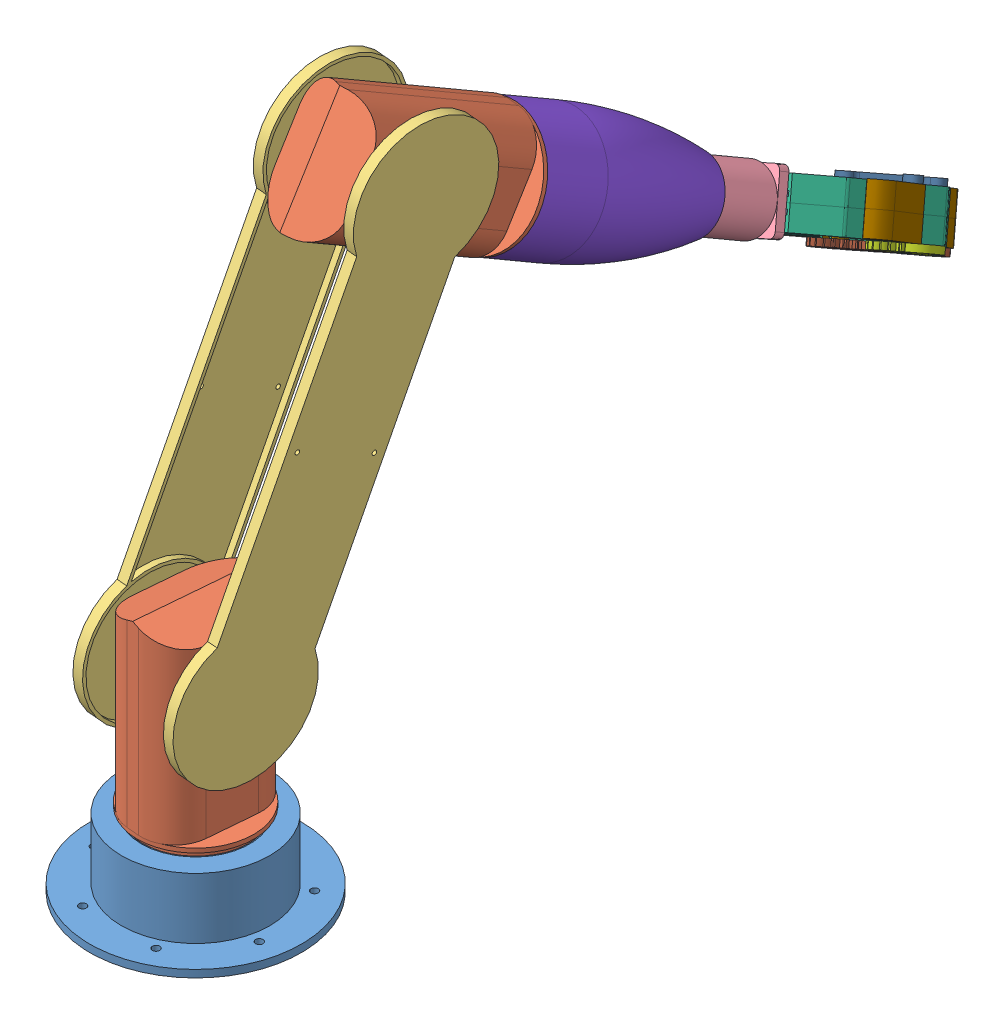
SolidWorks assembly robotic arm, configuration Default. Lengths in mm.
Overall size (112.51 303.58 382.68).
22 component instances, 12 part files, 42 mates.
Components (placement in the parent):
- base robot-1: base robot [Default] at (1.4403 12.4441 72.5801) size (100 32.2 100)
- hombrom robot-1: hombrom robot [Default] at (1.4403 49.6441 72.5801) x (-0.996236 0 -0.08668) z (-0.08668 0 0.996236) size (55 90.92 55)
- robot lateral-1: robot lateral [Default] at (-21.0498 188.2804 31.1109) x (0.036202 0.908608 -0.416079) z (0.996236 0 0.08668) size (252 63.5 8)
- robotarm1-1: robotarm1 [Default] at (22.4785 185.0491 -169.2166) x (0.927783 0.355674 -0.112755) z (0.076209 -0.476463 -0.875885) size (27.94 27.75 32.75)
- robotarm2-1: robotarm2 [Default] at (24.1156 180.8277 -169.0612) x (-0.076209 0.476463 0.875885) z (0.927783 0.355674 -0.112755) size (14 10 20)
- robotarm3-1: robotarm3 [Default] at (25.5753 158.2899 -228.1443) x (-0.927783 -0.355674 0.112755) z (-0.076209 0.476463 0.875885) size (41 10 82)
- robotarm5-1: robotarm5 [Default] at (44.119 149.8671 -221.8466) x (0.700809 0.569229 0.429937) z (0.612746 -0.171756 -0.77139) size (46.27 3 30.4)
- rotor robot-1: rotor robot [Default] at (15.4052 229.2716 -87.9219) x (0.955999 0.284504 -0.071585) z (-0.2833 0.83189 -0.47718) size (55 100.8 55)
- robot lateral-2: robot lateral [Default] at (30.7545 188.2804 35.6183) x (0.036202 0.908608 -0.416079) z (-0.996236 0 -0.08668) size (252 63.5 8)
- hombrom robot-2: hombrom robot [Default] at (12.3035 248.6641 -52.2727) x (-0.996236 0 -0.08668) z (-0.0413 -0.879194 0.47467) size (55 90.92 55)
- robotarm2-2: robotarm2 [Default] at (21.1461 187.3645 -172.8755) x (-0.076209 0.476463 0.875885) z (-0.927783 -0.355674 0.112755) size (14 10 20)
- robotarm3-2: robotarm3 [Default] at (29.2278 150.2495 -223.4527) x (-0.927783 -0.355674 0.112755) z (-0.076209 0.476463 0.875885) size (41 10 82)
- robotarm7-3: robotarm7 [Default] at (38.4459 147.7495 -234.9136) x (-0.365254 0.804039 -0.46916) z (-0.305764 -0.57964 -0.755332) size (10 10.69 76.99)
- robotarm7-4: robotarm7 [Default] at (34.7934 155.7899 -239.6053) x (-0.365254 0.804039 -0.46916) z (-0.305764 -0.57964 -0.755332) size (10 10.69 76.99)
- robotarm6-3: robotarm6 [Default] at (37.5467 141.412 -228.0229) x (-0.56216 -0.59222 -0.577279) z (-0.365254 0.804039 -0.46916) size (38 7 3)
- robotarm6-4: robotarm6 [Default] at (29.1459 159.9049 -238.8136) x (-0.56216 -0.59222 -0.577279) z (-0.365254 0.804039 -0.46916) size (38 7 3)
- Part11^robotic arm-1: Part11^robotic arm [Default] at origin (virtual)
- robotarm4-2: robotarm4 [Default] at (19.5122 139.8433 -219.8682) x (0.54358 -0.224923 -0.80866) z (-0.755719 -0.550392 -0.354905) size (49.54 3 29.07)
- robotarm7-7: robotarm7 [Default] at (18.1758 149.4194 -237.5857) x (0.365254 -0.804039 0.46916) z (0.445144 -0.291772 -0.846591) size (10 10.69 76.99)
- robotarm7-8: robotarm7 [Default] at (21.8283 141.379 -232.8941) x (0.365254 -0.804039 0.46916) z (0.445144 -0.291772 -0.846591) size (10 10.69 76.99)
- robotarm6-5: robotarm6 [Default] at (18.6049 158.6961 -239.0732) x (0.675705 -0.117673 -0.727719) z (0.365254 -0.804039 0.46916) size (38 7 3)
- robotarm6-6: robotarm6 [Default] at (27.0057 140.2032 -228.2825) x (0.675705 -0.117673 -0.727719) z (0.365254 -0.804039 0.46916) size (38 7 3)
Mates (geometry in assembly coordinates):
- Concentric1: concentric anti-aligned: cylinder of base robot-1 through (1.4403 44.6441 72.5801) axis (0 -1 0) radius 25.5; cylinder of hombrom robot-1 through (1.4403 44.6441 72.5801) axis (0 1 0) radius 25
- Coincident1: coincident anti-aligned: plane of base robot-1 through (1.4403 44.6441 72.5801) normal (0 1 0); plane of hombrom robot-1 through (1.4403 44.6441 72.5801) normal (0 -1 0)
- Concentric2: concentric anti-aligned: cylinder of hombrom robot-1 through (-22.4694 102.6441 70.4997) axis (0.996236 0 0.08668) radius 2.5; cylinder of robot lateral-1 through (-16.4919 102.6441 71.0198) axis (-0.996236 0 -0.08668) radius 5.75
- Coincident2: coincident aligned: circle of hombrom robot-1; plane of robot lateral-1 through (-22.4694 102.6441 70.4997) normal (0.996236 0 0.08668)
- Concentric3: concentric anti-aligned: cylinder of hombrom robot-1 through (25.35 102.6441 74.6604) axis (-0.996236 0 -0.08668) radius 2.5; cylinder of robot lateral-2 through (19.3726 102.6441 74.1403) axis (0.996236 0 0.08668) radius 5.75
- Coincident3: coincident anti-aligned: plane of hombrom robot-1 through (25.35 102.6441 74.6604) normal (0.996236 0 0.08668); plane of robot lateral-2 through (25.35 102.6441 74.6604) normal (-0.996236 0 -0.08668)
- Concentric4: concentric anti-aligned: cylinder of robot lateral-1 through (-9.6679 273.9166 -7.4111) axis (-0.996236 0 -0.08668) radius 5.75; cylinder of hombrom robot-2 through (-15.6453 273.9166 -7.9311) axis (0.996236 0 0.08668) radius 2.5
- Coincident4: coincident anti-aligned: plane of robot lateral-1 through (-22.4694 102.6441 70.4997) normal (0.996236 0 0.08668); plane of hombrom robot-2 through (-15.6453 273.9166 -7.9311) normal (-0.996236 0 -0.08668)
- Concentric5: concentric anti-aligned: cylinder of robot lateral-2 through (26.1966 273.9166 -4.2906) axis (0.996236 0 0.08668) radius 5.75; cylinder of hombrom robot-2 through (32.1741 273.9166 -3.7705) axis (-0.996236 0 -0.08668) radius 2.5
- Concentric6: concentric anti-aligned: cylinder of rotor robot-1 through (20.1377 199.6836 -142.3137) axis (0.076209 -0.476463 -0.875885) radius 27.5; cylinder of hombrom robot-2 through (12.6845 246.2817 -56.6522) axis (-0.076209 0.476463 0.875885) radius 25
- Coincident5: coincident anti-aligned: plane of rotor robot-1 through (38.7458 255.535 -55.9931) normal (-0.076209 0.476463 0.875885); plane of hombrom robot-2 through (12.4559 247.7111 -54.0245) normal (0.076209 -0.476463 -0.875885)
- Coincident6: coincident anti-aligned: plane of robotarm1-1 through (20.1377 199.6836 -142.3137) normal (-0.076209 0.476463 0.875885); plane of rotor robot-1 through (33.3001 203.6007 -143.2993) normal (0.076209 -0.476463 -0.875885)
- Concentric7: concentric anti-aligned: circle of robotarm1-1; circle of rotor robot-1
- Coincident7: coincident anti-aligned: plane of robotarm1-1 through (22.4785 185.0491 -169.2166) normal (0.076209 -0.476463 -0.875885); plane of robotarm2-2 through (8.7938 191.193 -173.7494) normal (-0.076209 0.476463 0.875885)
- Coincident8: coincident anti-aligned: plane of robotarm1-1 through (30.245 198.389 -178.1174) normal (0.365254 -0.804039 0.46916); plane of robotarm2-2 through (8.9463 190.2401 -175.5012) normal (-0.365254 0.804039 -0.46916)
- Width1: width aligned: plane of robotarm2-2 through (30.2111 191.1626 -174.9938) normal (0.927783 0.355674 -0.112755); plane of robotarm1-1 through (12.6549 181.8488 -171.4548) normal (-0.927783 -0.355674 0.112755); plane of robotarm2-2 through (6.208 189.1742 -175.1961) normal (0.927783 0.355674 -0.112755); plane of robotarm1-1 through (30.245 198.389 -178.1174) normal (-0.927783 -0.355674 0.112755)
- Coincident9: coincident anti-aligned: plane of robotarm2-1 through (36.1631 178.9051 -164.6837) normal (-0.076209 0.476463 0.875885); plane of robotarm1-1 through (22.4785 185.0491 -169.2166) normal (0.076209 -0.476463 -0.875885)
- Coincident11: coincident anti-aligned: plane of robotarm1-1 through (39.0586 178.9876 -166.7966) normal (-0.365254 0.804039 -0.46916); plane of robotarm2-1 through (36.3155 177.9521 -166.4355) normal (0.365254 -0.804039 0.46916)
- Width2: width anti-aligned: plane of robotarm2-1 through (32.7191 185.6416 -171.7722) normal (0.927783 0.355674 -0.112755); plane of robotarm1-1 through (15.163 176.3278 -168.2332) normal (-0.927783 -0.355674 0.112755); plane of robotarm2-1 through (30.245 198.389 -178.1174) normal (-0.927783 -0.355674 0.112755); plane of robotarm1-1 through (6.208 189.1742 -175.1961) normal (0.927783 0.355674 -0.112755)
- Coincident13: coincident aligned: plane of robotarm3-1 through (33.2175 185.6262 -176.5881) normal (-0.076209 0.476463 0.875885); plane of robotarm3-2 through (36.8701 177.5858 -171.8965) normal (-0.076209 0.476463 0.875885)
- Coincident14: coincident aligned: plane of robotarm3-1 through (47.1832 156.7963 -236.8688) normal (0.927783 0.355674 -0.112755); plane of robotarm3-2 through (50.8357 148.756 -232.1772) normal (0.927783 0.355674 -0.112755)
- Coincident15: coincident aligned: plane of robotarm3-1 through (33.2175 185.6262 -176.5881) normal (-0.076209 0.476463 0.875885); plane of robotarm3-2 through (36.8701 177.5858 -171.8965) normal (-0.076209 0.476463 0.875885)
- Coincident16: coincident anti-aligned: plane of robotarm3-1 through (27.4015 154.2697 -225.7985) normal (0.365254 -0.804039 0.46916); plane of robotarm3-2 through (27.4015 154.2697 -225.7985) normal (-0.365254 0.804039 -0.46916)
- Width3: width anti-aligned: plane of robotarm3-1 through (23.749 162.31 -230.4901) normal (-0.365254 0.804039 -0.46916); plane of robotarm2-2 through (31.0541 146.2293 -221.1069) normal (0.365254 -0.804039 0.46916); plane of robotarm3-2 through (12.5988 182.1997 -170.8096) normal (0.365254 -0.804039 0.46916); plane of robotarm2-1 through (32.663 185.9925 -171.1271) normal (-0.365254 0.804039 -0.46916)
- Concentric10: concentric aligned: cylinder of robotarm3-1 through (28.8835 181.942 -179.5278) axis (-0.365254 0.804039 -0.46916) radius 1.5; cylinder of robotarm2-2 through (28.1292 183.6023 -180.4966) axis (-0.365254 0.804039 -0.46916) radius 1.5
- Concentric11: concentric aligned: cylinder of robotarm3-1 through (17.7501 177.6739 -178.1748) axis (-0.365254 0.804039 -0.46916) radius 1.5; cylinder of robotarm2-2 through (16.9958 179.3343 -179.1436) axis (-0.365254 0.804039 -0.46916) radius 1.5
- Concentric13: concentric aligned: cylinder of robotarm5-1 through (44.6749 148.6188 -221.2216) axis (-0.365254 0.804039 -0.46916) radius 1.5; cylinder of robotarm3-2 through (43.5791 151.0309 -222.6291) axis (-0.365254 0.804039 -0.46916) radius 1.5
- Coincident21: coincident anti-aligned: plane of robotarm5-1 through (43.5791 151.0309 -222.6291) normal (-0.365254 0.804039 -0.46916); plane of robotarm3-2 through (31.0541 146.2293 -221.1069) normal (0.365254 -0.804039 0.46916)
- Concentric22: concentric anti-aligned: cylinder of robotarm3-2 through (27.7374 134.6447 -238.3782) axis (-0.365254 0.804039 -0.46916) radius 1.5; cylinder of robotarm6-3 through (27.7374 134.6447 -238.3782) axis (0.365254 -0.804039 0.46916) radius 1.5
- Coincident38: coincident anti-aligned: plane of robotarm3-2 through (31.0541 146.2293 -221.1069) normal (0.365254 -0.804039 0.46916); plane of robotarm6-3 through (36.4509 143.8241 -229.4304) normal (-0.365254 0.804039 -0.46916)
- Coincident40: coincident anti-aligned: plane of robotarm3-1 through (23.749 162.31 -230.4901) normal (-0.365254 0.804039 -0.46916); plane of robotarm6-4 through (29.1459 159.9049 -238.8136) normal (0.365254 -0.804039 0.46916)
- Concentric28: concentric anti-aligned: cylinder of robotarm3-1 through (24.0849 142.6851 -243.0698) axis (-0.365254 0.804039 -0.46916) radius 1.5; cylinder of robotarm6-4 through (19.3366 153.1376 -249.1689) axis (0.365254 -0.804039 0.46916) radius 1.5
- Coincident49: coincident anti-aligned: plane of robotarm3-2 through (31.0541 146.2293 -221.1069) normal (0.365254 -0.804039 0.46916); plane of robotarm4-2 through (17.1158 134.6013 -230.1835) normal (-0.365254 0.804039 -0.46916)
- Concentric32: concentric aligned: cylinder of robotarm3-2 through (18.529 141.4277 -219.5847) axis (-0.365254 0.804039 -0.46916) radius 1.5; cylinder of robotarm4-2 through (19.6247 139.0156 -218.1772) axis (-0.365254 0.804039 -0.46916) radius 1.5
- Coincident57: coincident anti-aligned: plane of robotarm7-3 through (36.6197 151.7697 -237.2595) normal (-0.365254 0.804039 -0.46916); plane of robotarm7-4 through (36.6197 151.7697 -237.2595) normal (0.365254 -0.804039 0.46916)
- Coincident58: coincident aligned: plane of robotarm7-3 through (41.016 152.4319 -239.5473) normal (0.87926 0.132435 -0.457562); plane of robotarm7-4 through (37.3634 160.4723 -244.2389) normal (0.87926 0.132435 -0.457562)
- Concentric38: concentric aligned: cylinder of robotarm7-3 through (31.7274 142.4954 -249.3448) axis (0.365254 -0.804039 0.46916) radius 1.5; cylinder of robotarm7-4 through (28.0749 150.5358 -254.0364) axis (0.365254 -0.804039 0.46916) radius 1.5
- Concentric39: concentric anti-aligned: cylinder of robotarm7-3 through (31.7274 142.4954 -249.3448) axis (0.365254 -0.804039 0.46916) radius 1.5; cylinder of robotarm4-2 through (36.4757 132.0429 -243.2457) axis (-0.365254 0.804039 -0.46916) radius 1.5
- Concentric40: concentric aligned: cylinder of robotarm7-3 through (41.5119 161.0439 -225.1741) axis (0.365254 -0.804039 0.46916) radius 1.5; cylinder of robotarm6-4 through (36.7636 171.4964 -231.2732) axis (0.365254 -0.804039 0.46916) radius 1.5
- Concentric41: concentric aligned: cylinder of robotarm7-3 through (41.5119 161.0439 -225.1741) axis (0.365254 -0.804039 0.46916) radius 1.5; cylinder of robotarm6-3 through (45.1644 153.0035 -220.4825) axis (0.365254 -0.804039 0.46916) radius 1.5
- Coincident60: coincident anti-aligned: plane of robotarm7-3 through (40.2722 143.7293 -232.5678) normal (0.365254 -0.804039 0.46916); plane of robotarm6-3 through (36.4509 143.8241 -229.4304) normal (-0.365254 0.804039 -0.46916)
- Concentric45: concentric aligned: cylinder of robotarm5-1 through (31.8727 130.2783 -242.6863) axis (-0.365254 0.804039 -0.46916) radius 1.5; cylinder of robotarm7-7 through (27.1244 140.7308 -248.7853) axis (-0.365254 0.804039 -0.46916) radius 1.5
